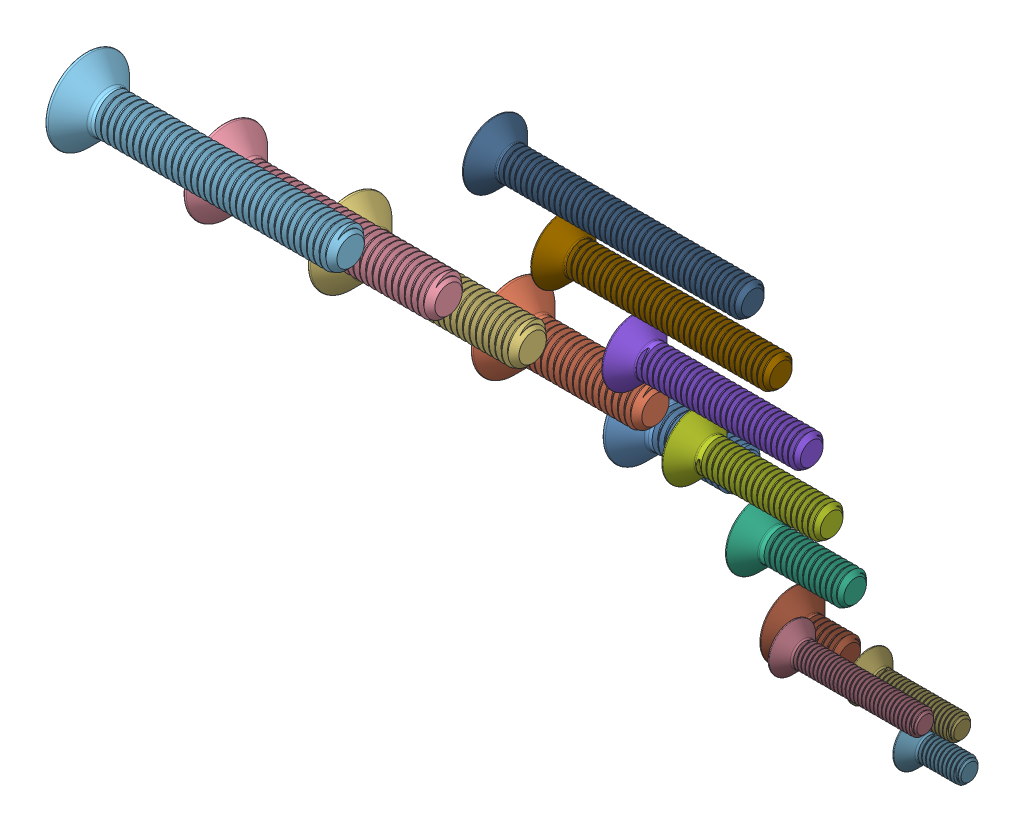
SolidWorks assembly All_Screws_assembly, configuration Default. Lengths in mm.
Overall size (81.8 74.29 53.06).
14 component instances, 14 part files, 0 mates.
Components (placement in the parent):
- M5_Countersunk_10-1: M5_Countersunk_10 [Default] at (-2.2089 5.7246 10.8892) size (12.9 10.23 10.23)
- M5_Countersunk_15-1: M5_Countersunk_15 [Default] at (-8.7101 16.7471 20.7848) size (17.9 10.23 10.23)
- M5_Countersunk_20-1: M5_Countersunk_20 [Default] at (-16.8792 27.9017 32.8932) size (22.9 10.23 10.23)
- M5_Countersunk_25-1: M5_Countersunk_25 [Default] at (-22.0837 38.0954 43.1388) size (27.93 10.23 10.23)
- M5_Countersunk_30-1: M5_Countersunk_30 [Default] at (-28.6961 47.7246 53.7141) size (32.96 10.23 10.23)
- M4_Counter_sunk_10-1: M4_Counter_sunk_10 [Default] at (36.4597 4.2158 15.3819) size (12.17 8.04 8.04)
- M4_Counter_sunk_15-1: M4_Counter_sunk_15 [Default] at (35.15 16.5558 21.9958) size (17.2 8.04 8.04)
- M4_Counter_sunk_20-1: M4_Counter_sunk_20 [Default] at (35.3295 30.608 29.6472) size (22.23 8.04 8.04)
- M4_Counter_sunk_25-1: M4_Counter_sunk_25 [Default] at (34.2799 44.9718 37.4326) size (27.31 8.04 8.04)
- M4_Counter_sunk_30-1: M4_Counter_sunk_30 [Default] at (32.9136 58.1316 44.5634) size (32.33 8.04 8.04)
- M4_Counter_sunk_5-1: M4_Counter_sunk_5 [Default] at (36.4376 -7.5449 11.0807) size (7.19 8.04 8.04)
- M3_Countersunk_Screw_10-1: M3_Countersunk_Screw_10 [Default] at (35.7195 1.4047 20.8393) size (11.72 5.84 5.84)
- M3_Countersunk_Screw_15-1: M3_Countersunk_Screw_15 [Default] at (36.3545 9.8949 31.0732) size (16.75 5.84 5.84)
- M3_Countersunk_Screw_5-1: M3_Countersunk_Screw_5 [Default] at (35.128 -9.219 14.3375) size (6.69 5.84 5.84)
